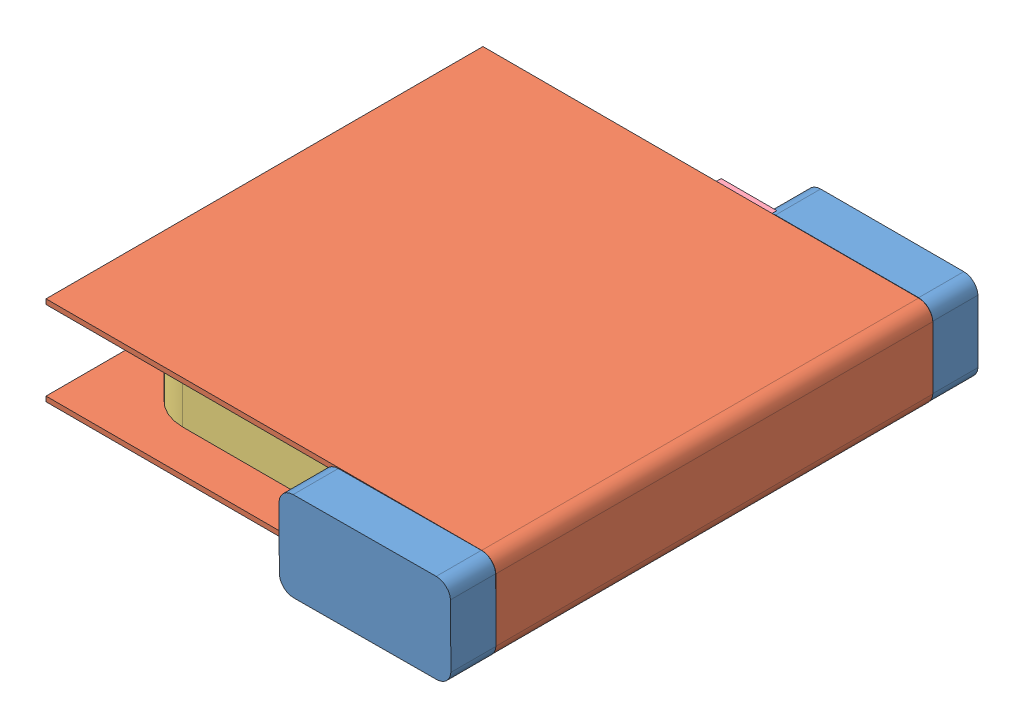
SolidWorks assembly House assembly, configuration Default. Lengths in mm.
Overall size (9970.55 2003.71 11680).
8 component instances, 5 part files, 6 mates.
Components (placement in the parent):
- Side car from roof-1: Side car from roof [Default] at (-9487.3309 6243.5875 -1758.698) size (3800 1976 1000)
- Angled Roof v4-1: Angled Roof v4 [Default] at (-9487.178 6236.0258 -758.698) size (9966.8 1976 9680)
- Main house glass-2: Main house glass [Default] at (-9599.3388 6236.0258 -678.4909) size (8706.67 1977.37 7680)
- Side car from roof-2: Side car from roof [Default] at (4125.5201 6261.2011 9921.302) x (-0.999986 -0.005207 0) z (0 0 -1) size (3800 1976 1000)
- House side support-1: House side support [Default] at (-4565.6166 9192.4429 4081.302)
- House side support-2: House side support [Default] at (-4457.5479 8878.0612 4081.302)
- House side support-3: House side support [Default] at (-6628.7468 12850.0203 4081.302)
- House support from sidecar-2: House support from sidecar [Default] at (-13971.534 6232.6515 -868.698) size (1300 1976 110)
Mates (geometry in assembly coordinates):
- Coincident4: coincident anti-aligned: plane of Angled Roof v4-1 through (-892.671 7918.8285 8921.302) normal (-1 0 0); plane of Main house glass-2 through (-892.671 7915.893 8001.5091) normal (1 0 0)
- Coincident5: coincident anti-aligned: plane of Angled Roof v4-1 through (-892.671 7918.8285 8921.302) normal (-1 0 0); plane of Main house glass-2 through (-892.671 7915.893 8001.5091) normal (1 0 0)
- Coincident6: coincident: line of Angled Roof v4-1 through (-1097.4737 6236.0258 241.302) axis (-1 0 0); plane of Main house glass-2 through (-8644.0745 6236.0258 1320.6678) normal (0 -1 0)
- Coincident7: coincident anti-aligned: plane of Side car from roof-1 through (-4268.0213 6559.1861 -758.698) normal (0 0 1); plane of Angled Roof v4-1 through (-1097.4737 6551.6245 -758.698) normal (0 0 -1)
- Coincident9: coincident anti-aligned: plane of Angled Roof v4-1 through (-1097.4737 6551.6245 8921.302) normal (0 0 1); plane of Side car from roof-2 through (-1095.362 6549.6191 8921.302) normal (0 0 -1)
- Coincident10: coincident anti-aligned: plane of Angled Roof v4-1 through (-1097.4737 6551.6245 -758.698) normal (0 0 -1); plane of House support from sidecar-2 through (-5581.8296 6548.2502 -758.698) normal (0 0 1)
